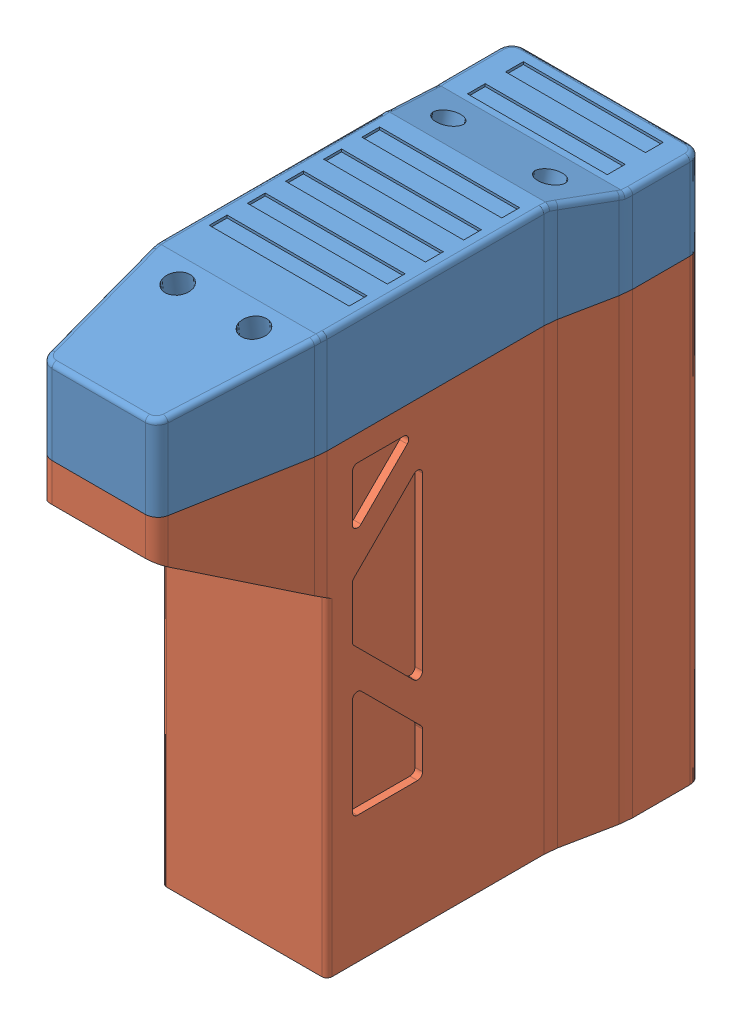
SolidWorks assembly 0, configuration 默认. Lengths in mm.
Overall size (75 220.11 200).
2 component instances, 2 part files, 3 mates.
Components (placement in the parent):
- 1-1: 1 [默认] at (-16.42 -15.1814 200) size (75 40.11 200)
- 2-1: 2 [默认] at (-21.42 -15.1814 200.1106) x (0 -1 0) z (-1 0 0) size (180 200 75)
Mates (geometry in assembly coordinates):
- 重合1: coincident anti-aligned: plane of 1-1 through (-16.42 -15.1814 200) normal (0 -1 0); plane of 2-1 through (11.08 -15.1814 105) normal (0 1 0)
- 重合2: coincident aligned: plane of 1-1 through (-58.92 17.8186 100) normal (0 0 -1); plane of 2-1 through (-53.92 -155.1814 100) normal (0 0 -1)
- 重合3: coincident aligned: plane of 1-1 through (-53.92 17.8186 155) normal (-1 0 0); plane of 2-1 through (-53.92 -155.1814 242.7458) normal (-1 0 0)
